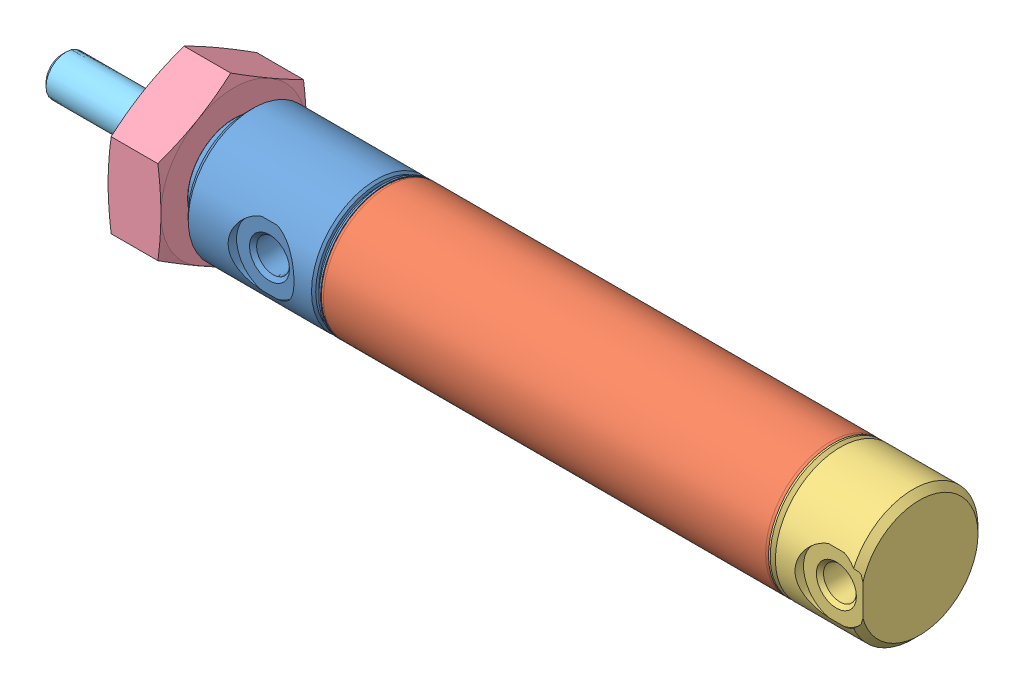
SolidWorks assembly 021_25-DQ, configuration Default. Lengths in mm.
Overall size (103.17 20.24 17.53).
6 component instances, 6 part files, 4 mates.
Components (placement in the parent):
- 021_25-DQ0000_0_dummy-1: 021_25-DQ0000_0_dummy [Default] at origin
- 02RQ000-0_rod_guide-1: 02RQ000-0_rod_guide [Default] at origin size (29.36 15.62 15.62)
- 02R-2_1380-1: 02R-2_1380 [Default] at (26.0096 0 0) size (55.42 15.62 15.62)
- 02PQ0000_rear_head-1: 02PQ0000_rear_head [Default] at (76.962 0 0) size (13.51 15.62 15.62)
- D-154-1: D-154 [Default] at (7.9502 0 0) x (0 0 -1) z (1 0 0) size (17.53 20.24 6.35)
- 021_25-DQ0_rod-1: 021_25-DQ0_rod [Default] at origin size (89.66 14.44 14.44)
Mates (geometry in assembly coordinates):
- Concentric3: concentric aligned: cylinder of 02RQ000-0_rod_guide-1 through (29.3624 0 0) axis (-1 0 0) radius 7.8105; cylinder of 021_25-DQ0_rod-1 through (0 0 0) axis (-1 0 0) radius 2.413
- Concentric4: concentric aligned: cylinder of 02R-2_1380-1 through (80.3148 0 0) axis (-1 0 0) radius 7.8105; cylinder of 021_25-DQ0_rod-1 through (0 0 0) axis (-1 0 0) radius 2.413
- Concentric9: concentric anti-aligned: cylinder of 02RQ000-0_rod_guide-1 through (29.3624 0 0) axis (-1 0 0) radius 7.8105; circle of D-154-1
- Concentric10: concentric aligned: cylinder of 02R-2_1380-1 through (80.3148 0 0) axis (-1 0 0) radius 7.8105; cylinder of 02PQ0000_rear_head-1 through (90.4748 0 0) axis (-1 0 0) radius 7.8105
